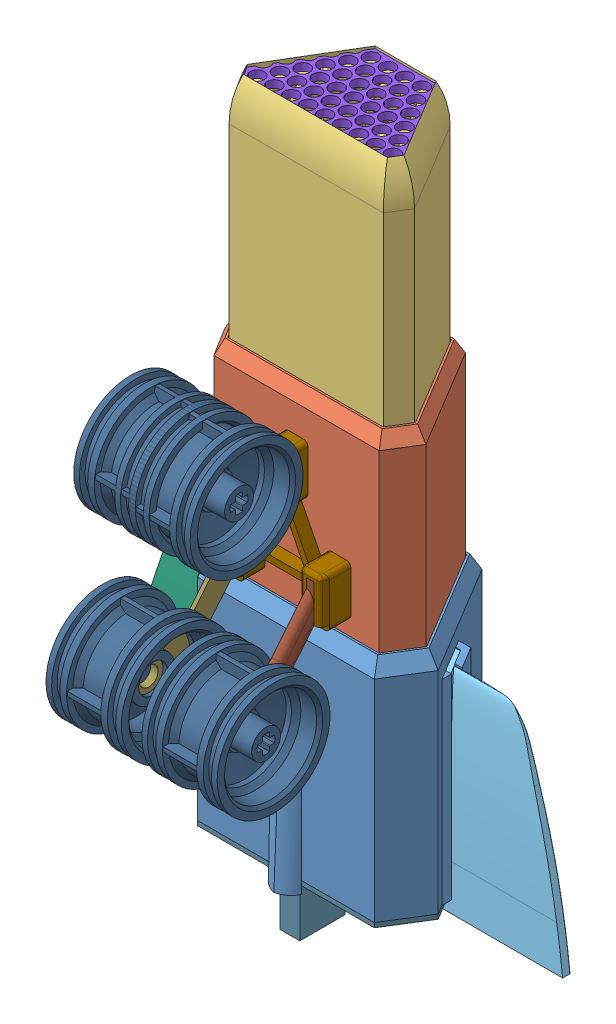
SolidWorks assembly Model Assembly1, configuration Default. Lengths in mm.
Overall size (116.44 185.2 90.99).
17 component instances, 14 part files, 43 mates.
Components (placement in the parent):
- Body_Back-1: Body_Back [Default] at (44.2014 -3.1926 57.4088) size (60 63.2 47.46)
- Body_Middle-1: Body_Middle [Default] at (44.2014 54.2074 44.2427) size (53.44 52.6 34)
- Body_Front-1: Body_Front [Default] at (44.771 104.2074 36.8968) x (1 0 0) z (0 1 0) size (47.34 28.8 62.6)
- Lock-1: Lock [Default] at (47.5081 -6.1926 13.8425) x (-1 0 0) z (0 0 -1) size (9.71 41.5 8.81)
- Wing_LeftSLDPRT-1: Wing_LeftSLDPRT [Default] at (68.4773 48.6074 38.5779) x (-1 0 0) z (0 0 1) size (38.95 59.3 6.96)
- Wing_Right-1: Wing_Right [Default] at (5.4711 -6.3926 39.6017) x (1 0 0) z (0 1 0) size (39.45 7.37 59.66)
- Frame_Clip_2-1: Frame_Clip_2 [Default] at (43.4211 73.3423 58.8088) x (-1 0 0) z (0 -1 0) size (25.95 8.66 33.66)
- Faceplate-1: Faceplate [Default] at (43.9749 164.2074 37.6088) size (41.72 2 24)
- Longer Frame-1: Longer Frame [Default] at (44.1072 83.9516 54.6088) x (1 0 0) z (0 -1 0) size (29.14 7.7 35.43)
- Rims-1: Rims [Default] at (56.8218 49.4357 83.3088) x (1 0 0) z (0 -0.00976 0.999952) size (20 30 30)
- Rims-2: Rims [Default] at (31.3686 49.4357 83.3088) x (-1 0 0) z (0 -0.004775 0.999989) size (20 30 30)
- Rims-3: Rims [Default] at (38.7436 101.1525 83.3088) x (-1 0 0) z (0 0.11908 0.992885) size (20 30 30)
- Rims-4: Rims [Default] at (49.6461 101.1525 83.3088) x (1 0 0) z (0 -0.012611 0.99992) size (20 30 30)
- Arm_BackLeft-2: Arm_BackLeft [Default] at (56.5589 60.9183 68.9091) x (0 -1 0) z (0 0 -1) size (27.13 3.45 27.5)
- Arm_Back_Right-3: Arm_Back_Right [Default] at (33.6714 60.9183 68.9091) x (0 -1 0) z (0 0 -1) size (27.13 3.45 27.5)
- Arm_Front-1: Arm_Front [Default] at (43.1041 98.0483 67.6551) x (0 -0.226717 -0.973961) z (0 -0.973961 0.226717) size (30.7 10.23 16.05)
- Big Finale-1: Big Finale [Default] at (44.2014 -4.3926 37.3057) x (-1 0 0) z (0 0 -1) size (60 18.4 39.6)
Mates (geometry in assembly coordinates):
- Coincident1: coincident: plane of Body_Back-1 through (44.2014 54.2074 57.4088) normal (0 1 0); plane of Body_Middle-1 through (44.2014 54.2074 44.2427) normal (0 -1 0)
- Coincident4: coincident: plane of Body_Middle-1 through (44.2014 104.2074 44.2427) normal (0 1 0); plane of Body_Front-1 through (44.771 104.2074 36.8968) normal (0 -1 0)
- Coincident8: coincident: plane of Body_Back-1 through (31.7014 56.8074 17.8088) normal (0 0 -1); plane of Lock-1 through (39.4166 35.3074 17.8088) normal (0 0 1)
- Coincident9: coincident: plane of Body_Back-1 through (44.2014 -6.1926 57.4088) normal (0 -1 0); plane of Lock-1 through (47.5081 -6.1926 13.8425) normal (0 -1 0)
- Coincident11: coincident: plane of Body_Back-1 through (72.7545 48.8074 41.9487) normal (0 0 -1); plane of Wing_LeftSLDPRT-1 through (102.2628 -6.3926 41.9487) normal (0 0 1)
- Coincident12: coincident: plane of Body_Back-1 through (65.8789 48.8074 35.2612) normal (0.857363 0 -0.514712); plane of Wing_LeftSLDPRT-1 through (65.8789 -6.3926 35.2612) normal (-0.857363 0 0.514712)
- Coincident13: coincident: plane of Body_Back-1 through (-11.6993 -6.3926 86.0044) normal (0 -1 0); plane of Wing_LeftSLDPRT-1 through (68.4773 -6.3926 38.5779) normal (0 -1 0)
- Tangent1: tangent: plane of Body_Back-1 through (15.6483 48.8074 41.9487) normal (0 0 -1); face of Wing_Right-1
- Coincident14: coincident: plane of Body_Back-1 through (22.5239 48.8074 35.2612) normal (-0.857363 0 -0.514712); plane of Wing_Right-1 through (18.5092 48.6074 41.9487) normal (0.857363 0 0.514712)
- Coincident15: coincident: plane of Body_Back-1 through (100.1021 -6.3926 86.0044) normal (0 -1 0); plane of Wing_Right-1 through (5.4711 -6.3926 39.6017) normal (0 -1 0)
- Coincident16: coincident: plane of Body_Middle-1 through (42.4514 83.9516 44.8088) normal (1 0 0); plane of Frame_Clip_2-1 through (42.4514 83.8793 52.2088) normal (-1 0 0)
- Coincident17: coincident: plane of Body_Middle-1 through (34.5306 61.8643 44.8088) normal (0 1 0); plane of Frame_Clip_2-1 through (34.4364 61.8643 52.2088) normal (0 -1 0)
- Coincident18: coincident: plane of Body_Middle-1 through (23.5908 106.8074 52.2088) normal (0 0 -1); plane of Frame_Clip_2-1 through (31.2395 92.4313 52.2088) normal (0 0 1)
- Coincident20: coincident: plane of Frame_Clip_2-1 through (45.7514 94.1293 52.2088) normal (0 1 0); plane of ? through (44.0014 94.1293 59.5588) normal (0 -1 0)
- Coincident21: coincident: plane of Frame_Clip_2-1 through (45.7514 83.8793 52.2088) normal (1 0 0); plane of ? through (45.7514 83.6293 59.5588) normal (-1 0 0)
- Coincident23: coincident: plane of Body_Middle-1 through (22.1461 106.8074 54.8088) normal (0 0 1); plane of ? through (44.0014 83.6293 54.8088) normal (0 0 -1)
- Coincident24: coincident: plane of Body_Front-1 through (52.2864 164.2074 25.6088) normal (0 0 1); plane of Faceplate-1 through (52.2864 166.2074 25.6088) normal (0 0 -1)
- Coincident25: coincident: plane of Body_Front-1 through (65.0605 164.2074 46.8867) normal (-0.857363 0 0.514712); plane of Faceplate-1 through (65.0605 166.2074 46.8867) normal (0.857363 0 -0.514712)
- Coincident26: coincident: plane of Body_Front-1 through (44.771 164.2074 36.8968) normal (0 1 0); plane of Faceplate-1 through (43.9749 164.2074 37.6088) normal (0 -1 0)
- Coincident27: coincident: plane of Body_Back-1 through (24.5073 3.8074 29.792) normal (0.857363 0 0.514712); plane of ? through (31.7014 -3.1926 17.8088) normal (-0.857363 0 -0.514712)
- Coincident28: coincident: plane of Body_Back-1 through (36.7002 41.0074 17.8088) normal (0 0 1); plane of ? through (31.7014 -3.1926 17.8088) normal (0 0 -1)
- Coincident29: coincident: plane of Body_Back-1 through (44.2014 -3.1926 57.4088) normal (0 -1 0); plane of ? through (43.9749 -3.1926 38.0617) normal (0 1 0)
- Concentric1: concentric: cylinder of ? through (43.9749 -13.1926 38.0617) axis (0 1 0) radius 5; cylinder of ? through (43.9749 -8.6926 38.0617) axis (0 1 0) radius 6.25
- Coincident30: coincident: plane of ? through (43.9749 -5.1926 38.0617) normal (0 -1 0); plane of ? through (43.9749 -5.1926 38.0617) normal (0 1 0)
- Concentric2: concentric: cylinder of ? through (43.9749 -6.1926 38.0617) axis (0 -1 0) radius 5; cylinder of ? through (43.9749 -6.1926 38.0617) axis (0 -1 0) radius 5
- Coincident31: coincident: plane of ? through (43.9749 -6.1926 38.0617) normal (0 -1 0); plane of ? through (43.9749 -6.1926 38.0617) normal (0 1 0)
- Coincident32: coincident: plane of Frame_Clip_2-1 through (34.4364 61.8643 52.2088) normal (1 0 0); plane of Longer Frame-1 through (34.4364 83.9516 59.3588) normal (-1 0 0)
- Coincident33: coincident: plane of Frame_Clip_2-1 through (34.4364 61.8643 52.2088) normal (0 -1 0); plane of Longer Frame-1 through (44.1072 61.8643 59.3588) normal (0 1 0)
- Coincident34: coincident: plane of Body_Middle-1 through (66.1456 115.2074 54.6088) normal (0 0 1); plane of Longer Frame-1 through (44.1072 83.9516 54.6088) normal (0 0 -1)
- Coincident35: coincident: plane of Longer Frame-1 through (44.1072 83.9516 60.3088) normal (0 0 1); plane of Arm_BackLeft-2 through (54.5589 72.0418 60.3088) normal (0 0 -1)
- Coincident37: coincident: plane of Longer Frame-1 through (53.7933 72.0683 62.3088) normal (0 -1 0); plane of Arm_BackLeft-2 through (56.5589 72.0683 68.9091) normal (0 1 0)
- Lock1: lock: unknown of Body_Back-1; unknown of Body_Middle-1
- Coincident39: coincident: plane of Longer Frame-1 through (44.1072 83.9516 60.3088) normal (0 0 1); plane of Arm_Back_Right-3 through (31.6714 72.0418 60.3088) normal (0 0 -1)
- Coincident40: coincident: plane of Longer Frame-1 through (35.8364 72.0683 62.3088) normal (0 -1 0); plane of Arm_Back_Right-3 through (33.6714 72.0683 68.9091) normal (0 1 0)
- Concentric3: concentric: cylinder of Rims-1 through (56.8218 49.4357 83.3088) axis (-1 0 0) radius 3.805; cylinder of Arm_BackLeft-2 through (54.5589 49.4357 83.3088) axis (1 0 0) radius 2.5
- Concentric4: concentric: cylinder of Rims-2 through (31.3686 49.4357 83.3088) axis (1 0 0) radius 3.805; cylinder of Arm_Back_Right-3 through (31.6714 49.4357 83.3088) axis (1 0 0) radius 2.5
- Coincident41: coincident: plane of Longer Frame-1 through (44.1072 83.9516 60.3088) normal (0 0 1); plane of Arm_Front-1 through (45.1041 84.4049 60.3088) normal (0 0 -1)
- Coincident42: coincident: plane of Longer Frame-1 through (42.3725 94.2049 62.3088) normal (0 -1 0); plane of Arm_Front-1 through (43.1041 94.2049 67.6551) normal (0 1 0)
- Concentric5: concentric: cylinder of Rims-4 through (49.6461 101.1525 83.3088) axis (-1 0 0) radius 3.805; cylinder of Arm_Front-1 through (49.1041 101.1525 83.3088) axis (-1 0 0) radius 2.5
- Concentric6: concentric: cylinder of Rims-3 through (38.7436 101.1525 83.3088) axis (1 0 0) radius 3.805; cylinder of Arm_Front-1 through (49.1041 101.1525 83.3088) axis (-1 0 0) radius 2.5
- Coincident46: coincident: plane of Body_Back-1 through (44.2014 -3.1926 57.4088) normal (0 -1 0); plane of Big Finale-1 through (44.2014 -3.1926 37.3057) normal (0 1 0)
- Coincident47: coincident: plane of Body_Back-1 through (20.7014 56.8074 57.4088) normal (-0.849138 0 0.528172); plane of Big Finale-1 through (14.2014 -3.1926 46.9588) normal (-0.849138 0 0.528172)
- Coincident48: coincident: plane of Body_Back-1 through (31.7014 56.8074 17.8088) normal (-0.857363 0 -0.514712); plane of Big Finale-1 through (17.2092 -3.1926 41.9487) normal (-0.857363 0 -0.514712)
